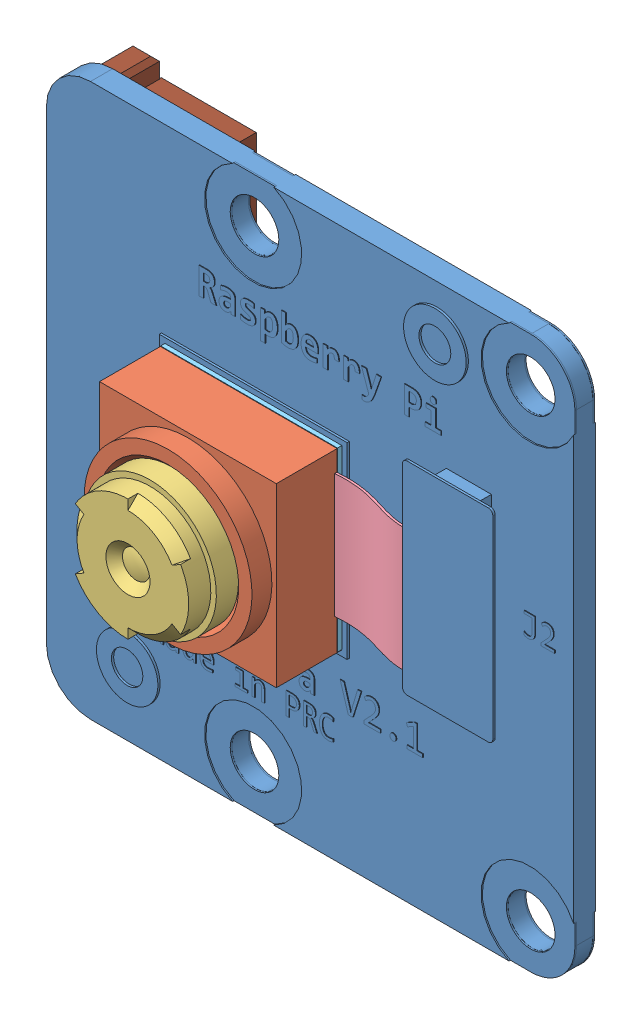
SolidWorks assembly RspCameraMia, configuration Default. Lengths in mm.
Overall size (23.86 25 9.96).
32 component instances, 15 part files, 0 mates.
Components (placement in the parent):
- PicameraPCB-1: PicameraPCB [Default] at (0.2393 -0.0199 0) x (-1 0 0) z (0 0 1) size (23.86 25 2.2)
- OVA5647_Housing-1: OVA5647_Housing [Default] at (-2.4078 0.0859 1) x (1 0 0) z (0 -1 0) size (8 3.95 8)
- OVA5647_Lens_FOV-1: OVA5647_Lens_FOV [Default] at (-2.4087 0.0921 5.963) x (1 0 0) z (0 -1 0) size (6 3.35 6)
- ribbon_cam-1: ribbon_cam [Default] at (-2.4804 0.3633 1.4162) x (0 1 0) z (1 0 0) size (5.6 1.19 4.76)
- CCD-1: CCD [Default] at (-2.0757 0.287 1.296) x (1 0 0) z (0 -1 0) size (8 0.68 8)
- CAPC-0805-T0.75-BN-1: CAPC-0805-T0.75-BN [Default] at (4.562 5.9833 -0.0026) x (0 -1 0) z (0 0 -1) size (2.1 1.35 0.75)
- CAPC-0805-T0.75-BN-2: CAPC-0805-T0.75-BN [Default] at (2.0233 10.2705 -0.0026) x (0 -1 0) z (0 0 -1) size (2.1 1.35 0.75)
- CAPC-0402-T0.55-BN-1: CAPC-0402-T0.55-BN [Default] at (-2.9562 6.224 -0.2572) x (-1 0 0) z (0 -1 0) size (1.05 0.55 0.55)
- CAPC-0402-T0.55-BN-2: CAPC-0402-T0.55-BN [Default] at (-2.9504 5.2898 -0.2691) x (-1 0 0) z (0 -1 0) size (1.05 0.55 0.55)
- CAPC-0402-T0.55-BN-3: CAPC-0402-T0.55-BN [Default] at (4.5768 -5.1833 -0.2811) x (-1 0 0) z (0 -1 0) size (1.05 0.55 0.55)
- CAPC-0402-T0.55-BN-4: CAPC-0402-T0.55-BN [Default] at (2.5547 -5.1368 -0.2811) x (-1 0 0) z (0 -1 0) size (1.05 0.55 0.55)
- CAPC-0402-T0.55-BN-5: CAPC-0402-T0.55-BN [Default] at (2.6129 -9.93 -0.293) x (-1 0 0) z (0 -1 0) size (1.05 0.55 0.55)
- CAPC-0402-T0.55-BN-6: CAPC-0402-T0.55-BN [Default] at (4.7286 -9.9294 -0.293) x (-1 0 0) z (0 -1 0) size (1.05 0.55 0.55)
- CAPC-0402-T0.55-BN-7: CAPC-0402-T0.55-BN [Default] at (8.4068 -3.8793 -0.2811) x (-1 0 0) z (0 -1 0) size (1.05 0.55 0.55)
- CAPC-0402-T0.55-BN-8: CAPC-0402-T0.55-BN [Default] at (9.0088 0.0217 -0.2796) x (0 1 0) z (-1 0 0) size (1.05 0.55 0.55)
- CAPC-0402-T0.55-BN-9: CAPC-0402-T0.55-BN [Default] at (10.4284 2.6731 -0.3022) x (0 1 0) z (-1 0 0) size (1.05 0.55 0.55)
- CAPC-0402-T0.55-BN-10: CAPC-0402-T0.55-BN [Default] at (8.2321 1.3259 -0.2838) x (1 0 0) z (0 1 0) size (1.05 0.55 0.55)
- RESC-0402-1: RESC-0402 [Default] at (3.7919 0.0148 -0.0114) x (1 0 0) z (0 0 -1) size (1.05 0.55 0.4)
- RESC-0402-2: RESC-0402 [Default] at (4.1232 2.6296 -0.0028) x (0 -1 0) z (0 0 -1) size (1.05 0.55 0.4)
- RESC-0402-3: RESC-0402 [Default] at (10.5883 -6.2795 -0.0019) x (0 1 0) z (0 0 -1) size (1.05 0.55 0.4)
- RESC-0603-1: RESC-0603 [Default] at (-2.6191 7.0617 -0.0121) x (1 0 0) z (0 0 -1) size (1.7 0.9 0.55)
- RESC-0603-2: RESC-0603 [Default] at (-3.4466 3.0018 -0.0048) x (0 -1 0) z (0 0 -1) size (1.7 0.9 0.55)
- RESC-1210-1: RESC-1210 [Default] at (2.2265 5.9002 -0.0068) x (0 -1 0) z (0 0 -1) size (3.3 2.7 0.6)
- c-1-1734248-5-e-raspberry_display-1: c-1-1734248-5-e-raspberry_display [Default] at (-10.6651 0.0449 -1.5) x (0 -1 0) z (-1 0 0) size (22.4 3.22 5.68)
- SOT23-5-1: SOT23-5 [Default] at (4.2989 9.8879 0.5457) x (0 -1 0) z (0 0 -1) size (2.91 3.01 1.23)
- SOT23-5-2: SOT23-5 [Default] at (3.5194 -3.2493 0.04) x (-1 0 0) z (0 0 -1) size (2.91 3.01 1.23)
- SOT23-5-3: SOT23-5 [Default] at (3.5816 -8.055 0.0206) x (-1 0 0) z (0 0 -1) size (2.91 3.01 1.23)
- KX7 SMD Quartz Crystal Resonator 3.2x2.5mm-1: KX7 SMD Quartz Crystal Resonator 3.2x2.5mm [Default] at (9.9746 -4.9221 0.0339) x (-1 0 0) z (0 -1 0) size (3.2 0.6 2.5)
- c6aaa-1: c6aaa [Default] at (0.0643 0.0942 0) x (1 0 0) z (0 0 -1) size (2.01 2.99 0.61)
- 4pin_smd-1: 4pin_smd [Default] at (0.027 0.0676 0) x (1 0 0) z (0 0 -1) size (1.29 1 0.47)
- 4pin_smd-2: 4pin_smd [Default] at (-0.0093 -6.0092 -0.0198) x (1 0 0) z (0 0 -1) size (1.29 1 0.47)
- 4pin_smd-3: 4pin_smd [Default] at (0.0326 -3.0068 -0.0235) x (1 0 0) z (0 0 -1) size (1.29 1 0.47)
